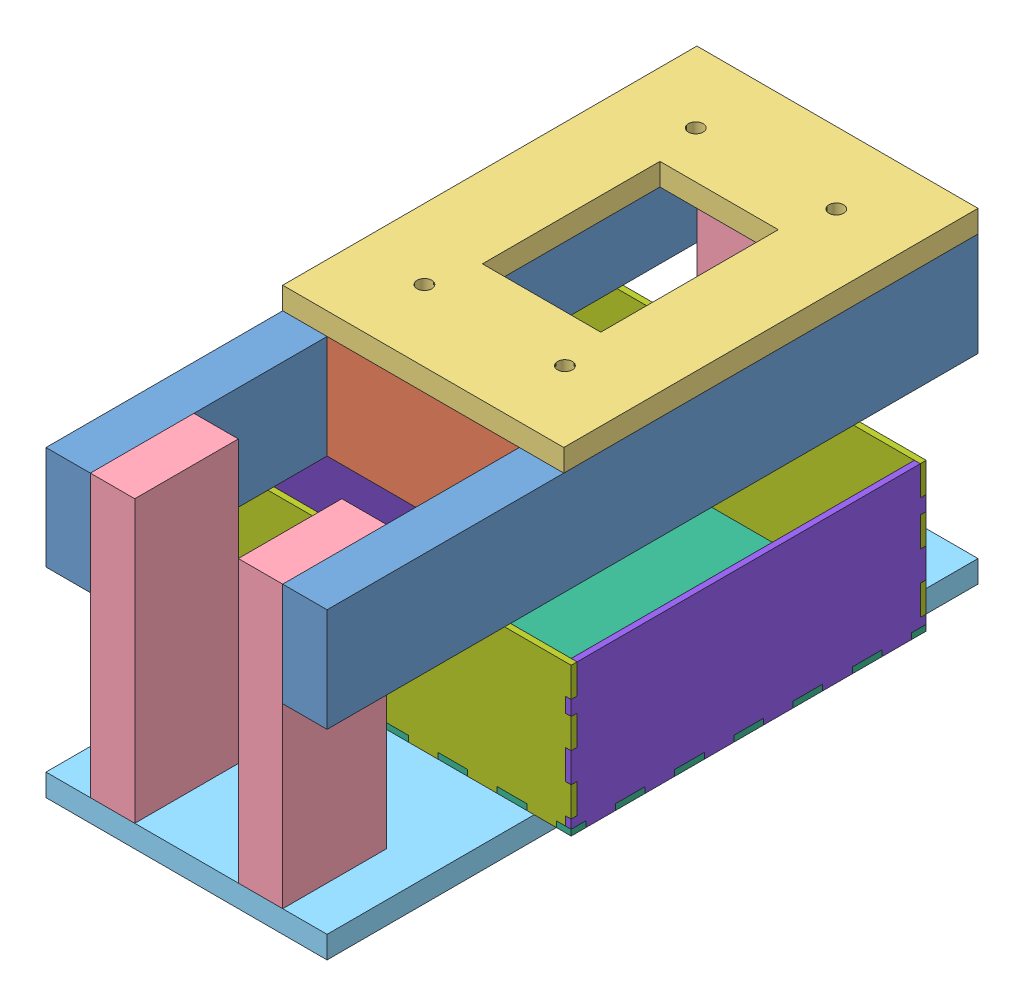
SolidWorks assembly Shredder_Chassis_Subassembly, configuration Default. Lengths in mm.
Overall size (304.8 279.4 558.8).
15 component instances, 8 part files, 27 mates.
Components (placement in the parent):
- Side_Wall-1: Side_Wall [Default] at origin size (38.1 88.9 558.8)
- 2x4x6.5-1: 2x4x6.5 [Default] at (101.6 0 -260.35) x (0 0 1) z (-1 0 0) size (38.1 88.9 165.1)
- Side_Wall-2: Side_Wall [Default] at (203.2 0 0) size (38.1 88.9 558.8)
- 2x4x6.5-2: 2x4x6.5 [Default] at (101.6 0 57.15) x (0 0 1) z (-1 0 0) size (38.1 88.9 165.1)
- Top_Plate-1: Top_Plate [Default] at (101.6 53.975 -101.6) size (241.3 19.05 355.6)
- 2x4x9.5-1: 2x4x9.5 [Default] at (38.1 -76.2 234.95) size (38.1 241.3 88.9)
- 2x4x9.5-2: 2x4x9.5 [Default] at (165.1 -76.2 234.95) size (38.1 241.3 88.9)
- 2x4x9.5-3: 2x4x9.5 [Default] at (101.6 -76.2 -222.25) x (0 0 -1) z (1 0 0) size (38.1 241.3 88.9)
- Bottom_Plate-1: Bottom_Plate [Default] at (101.6 -206.375 0) size (241.3 19.05 558.8)
- Box_Subassembly-1: Box_Subassembly [Default] at (101.6 -194.31 -50.8) size (304.8 127 304.8)
  - Box_Bottom-1: Box_Bottom [Default] at origin size (304.8 5.08 304.8)
  - Box_Side1-1: Box_Side1 [Default] at (0 124.46 149.86) size (304.8 127 5.08)
  - Box_Side1-2: Box_Side1 [Default] at (0 124.46 -149.86) size (304.8 127 5.08)
  - Box_Side2-1: Box_Side2 [Default] at (149.86 124.46 0) x (0 0 -1) z (1 0 0) size (304.8 127 5.08)
  - Box_Side2-2: Box_Side2 [Default] at (-149.86 124.46 0) x (0 0 -1) z (1 0 0) size (304.8 127 5.08)
Mates (geometry in assembly coordinates):
- Coincident1: coincident anti-aligned: plane of Side_Wall-1 through (19.05 -44.45 279.4) normal (1 0 0); plane of 2x4x6.5-1 through (19.05 0 -260.35) normal (-1 0 0)
- Coincident2: coincident aligned: plane of Side_Wall-1 through (19.05 44.45 279.4) normal (0 1 0); plane of 2x4x6.5-1 through (19.05 44.45 -241.3) normal (0 1 0)
- Coincident3: coincident aligned: plane of Side_Wall-1 through (0 0 -279.4) normal (0 0 -1); plane of 2x4x6.5-1 through (19.05 -44.45 -279.4) normal (0 0 -1)
- Coincident4: coincident anti-aligned: plane of 2x4x6.5-1 through (184.15 0 -260.35) normal (1 0 0); plane of Side_Wall-2 through (184.15 -44.45 279.4) normal (-1 0 0)
- Coincident5: coincident aligned: plane of 2x4x6.5-1 through (19.05 44.45 -241.3) normal (0 1 0); plane of Side_Wall-2 through (222.25 44.45 279.4) normal (0 1 0)
- Coincident6: coincident aligned: plane of 2x4x6.5-1 through (19.05 -44.45 -279.4) normal (0 0 -1); plane of Side_Wall-2 through (203.2 0 -279.4) normal (0 0 -1)
- Coincident7: coincident aligned: plane of Side_Wall-1 through (19.05 44.45 279.4) normal (0 1 0); plane of 2x4x6.5-2 through (19.05 44.45 76.2) normal (0 1 0)
- Coincident8: coincident anti-aligned: plane of Side_Wall-2 through (184.15 -44.45 279.4) normal (-1 0 0); plane of 2x4x6.5-2 through (184.15 0 57.15) normal (1 0 0)
- Distance1: distance = 279.4 mm anti-aligned: plane of 2x4x6.5-1 through (19.05 -44.45 -241.3) normal (0 0 1); plane of 2x4x6.5-2 through (19.05 -44.45 38.1) normal (0 0 -1)
- Coincident10: coincident aligned: plane of Side_Wall-2 through (222.25 -44.45 279.4) normal (1 0 0); plane of Top_Plate-1 through (222.25 63.5 -279.4) normal (1 0 0)
- Coincident11: coincident anti-aligned: plane of Side_Wall-2 through (222.25 44.45 279.4) normal (0 1 0); plane of Top_Plate-1 through (101.6 44.45 -101.6) normal (0 -1 0)
- Coincident12: coincident aligned: plane of 2x4x6.5-1 through (19.05 -44.45 -279.4) normal (0 0 -1); plane of Top_Plate-1 through (222.25 63.5 -279.4) normal (0 0 -1)
- Coincident13: coincident anti-aligned: plane of Side_Wall-1 through (19.05 -44.45 279.4) normal (1 0 0); plane of 2x4x9.5-1 through (19.05 44.45 279.4) normal (-1 0 0)
- Coincident14: coincident aligned: plane of Side_Wall-1 through (0 0 279.4) normal (0 0 1); plane of 2x4x9.5-1 through (57.15 44.45 279.4) normal (0 0 1)
- Coincident15: coincident aligned: plane of Side_Wall-1 through (19.05 44.45 279.4) normal (0 1 0); plane of 2x4x9.5-1 through (38.1 44.45 234.95) normal (0 1 0)
- Coincident16: coincident anti-aligned: plane of Side_Wall-2 through (184.15 -44.45 279.4) normal (-1 0 0); plane of 2x4x9.5-2 through (184.15 44.45 279.4) normal (1 0 0)
- Coincident17: coincident aligned: plane of Side_Wall-2 through (203.2 0 279.4) normal (0 0 1); plane of 2x4x9.5-2 through (184.15 44.45 279.4) normal (0 0 1)
- Coincident18: coincident aligned: plane of Side_Wall-2 through (222.25 44.45 279.4) normal (0 1 0); plane of 2x4x9.5-2 through (165.1 44.45 234.95) normal (0 1 0)
- Coincident19: coincident anti-aligned: plane of 2x4x6.5-1 through (19.05 -44.45 -241.3) normal (0 0 1); plane of 2x4x9.5-3 through (146.05 44.45 -241.3) normal (0 0 -1)
- Coincident20: coincident anti-aligned: plane of Top_Plate-1 through (101.6 44.45 -101.6) normal (0 -1 0); plane of 2x4x9.5-3 through (101.6 44.45 -222.25) normal (0 1 0)
- Coincident22: coincident aligned: plane of 2x4x9.5-3 through (101.6 -76.2 -222.25) normal (1 0 0)
- Coincident23: coincident anti-aligned: plane of 2x4x9.5-2 through (165.1 -196.85 234.95) normal (0 -1 0); plane of Bottom_Plate-1 through (101.6 -196.85 0) normal (0 1 0)
- Coincident24: coincident aligned: plane of 2x4x9.5-2 through (184.15 44.45 279.4) normal (0 0 1); plane of Bottom_Plate-1 through (222.25 -196.85 279.4) normal (0 0 1)
- Coincident25: coincident aligned: plane of Side_Wall-2 through (222.25 -44.45 279.4) normal (1 0 0); plane of Bottom_Plate-1 through (222.25 -196.85 279.4) normal (1 0 0)
- Coincident26: coincident: plane of Bottom_Plate-1 through (101.6 -196.85 0) normal (0 1 0); plane of Box_Subassembly-1/Box_Bottom-1 through (150.6488 -166.3236 -54.9581) normal (0 -1 0)
- Coincident28: coincident: plane of assembly; plane of Box_Subassembly-1 through (150.6488 -163.7836 -54.9581) normal (1 0 0); plane of assembly
- Coincident29: coincident anti-aligned: plane of 2x4x9.5-3 through (146.05 44.45 -203.2) normal (0 0 1); plane of Box_Subassembly-1/Box_Side1-2 through (101.6 -69.85 -203.2) normal (0 0 -1)
